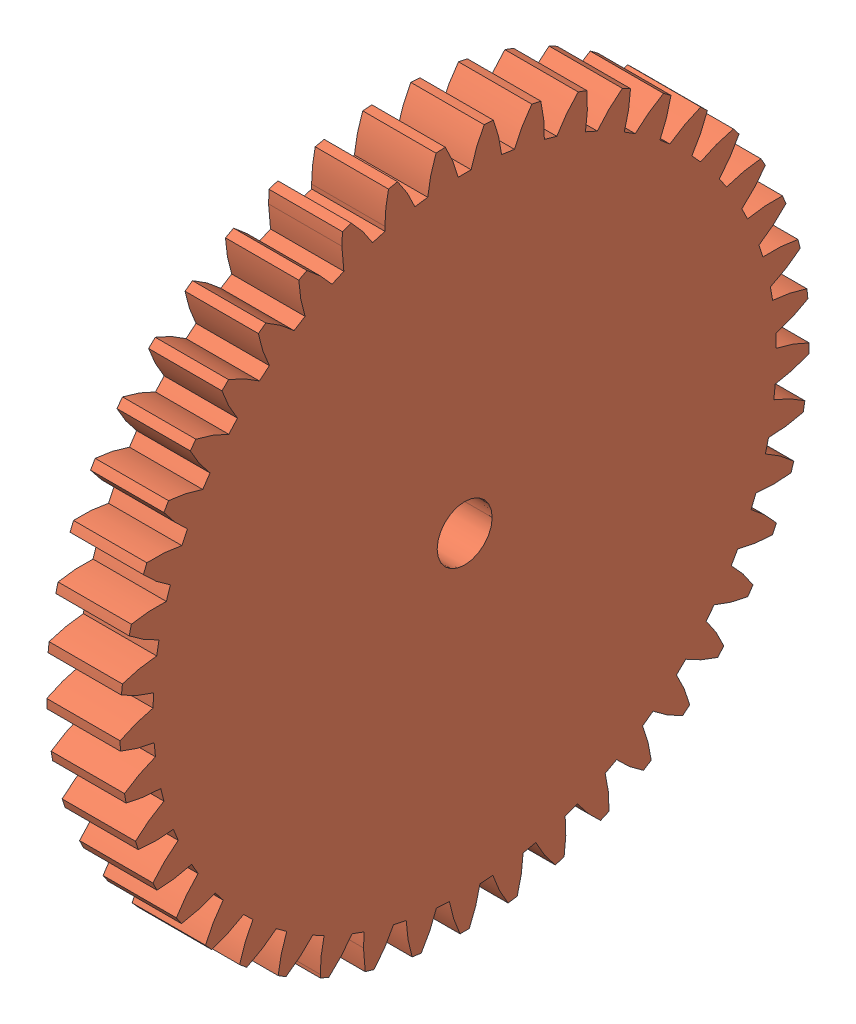
SolidWorks assembly Banh rang T45-T15, configuration Default. Lengths in mm.
Overall size (4 18.79 18.8).
2 component instances, 2 part files, 2 mates.
Components (placement in the parent):
- Spur gear 0.4M 15T 1.5N-1: Spur gear 0.4M 15T 1.5N [Default] at (-0.8782 5.44 4.254) size (2 6.74 6.78)
- Spur gear 0.4M 45T 1.5N-1: Spur gear 0.4M 45T 1.5N [Default] at (1.1218 5.44 4.254) size (2 18.79 18.8)
Mates (geometry in assembly coordinates):
- Coincident1: coincident anti-aligned: circle of Spur gear 0.4M 15T 1.5N-1; circle of Spur gear 0.4M 45T 1.5N-1
- Lock1: lock: unknown of Spur gear 0.4M 15T 1.5N-1; unknown of Spur gear 0.4M 45T 1.5N-1
